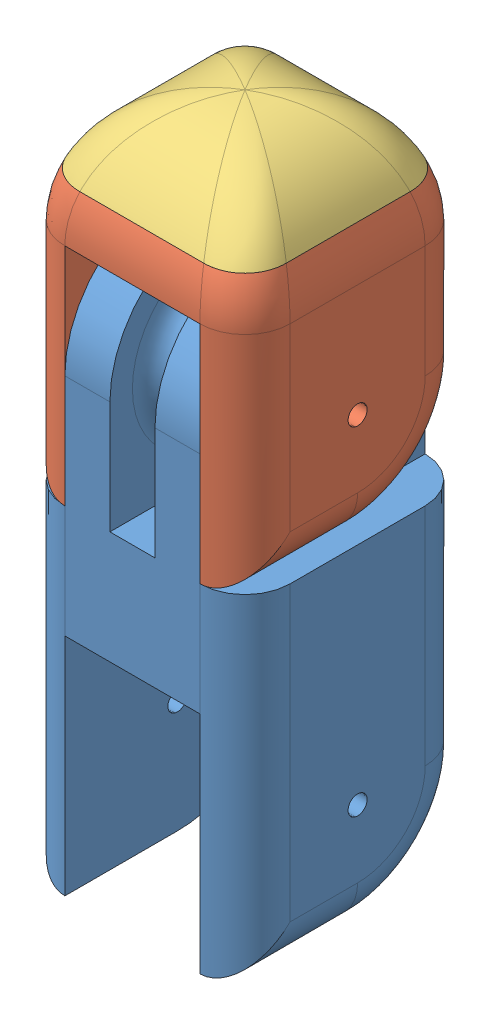
SolidWorks assembly Finger Assembly 1, configuration Default. Lengths in mm.
Overall size (20 60 20).
3 component instances, 3 part files, 6 mates.
Components (placement in the parent):
- Finger Body 1-2: Finger Body 1 [Default] at (8.0779 51.877 43.4324) size (20 50 20)
- Finger Top-1: Finger Top [Default] at (8.0779 81.877 43.4324) size (20 24 20)
- Finger Tip-1: Finger Tip [Default] at (8.0779 81.877 43.4324) size (18.77 6 18.77)
Mates (geometry in assembly coordinates):
- Coincident2: coincident anti-aligned: plane of Finger Body 4-2 through (14.0779 71.877 53.4324) normal (1 0 0); plane of Finger Top-1 through (14.0779 71.877 53.4324) normal (-1 0 0)
- Concentric2: concentric aligned: circle of Finger Body-2; circle of Finger Top-1
- LimitAngle2: limit planar angle = 1.570796 rad anti-aligned: plane of Finger Top-1 through (18.0779 85.877 27.2077) normal (0 1 0); plane of Finger Body-2 through (-1.9221 61.877 53.4324) normal (0 0 1)
- Coincident5: coincident anti-aligned: plane of Finger Top-1 through (18.0779 85.877 27.2077) normal (0 1 0); plane of Finger Tip-1 through (-1.9221 85.877 53.958) normal (0 -1 0)
- Coincident6: coincident anti-aligned: line of Finger Top-1 through (2.5788 85.877 52.5976) axis (1 0 0); line of Finger Tip-1 through (13.577 85.877 52.5976) axis (-1 0 0)
- Coincident7: coincident anti-aligned: line of Finger Top-1 through (-1.0873 85.877 37.9334) axis (0 0 1); line of Finger Tip-1 through (-1.0873 85.877 48.9315) axis (0 0 -1)
